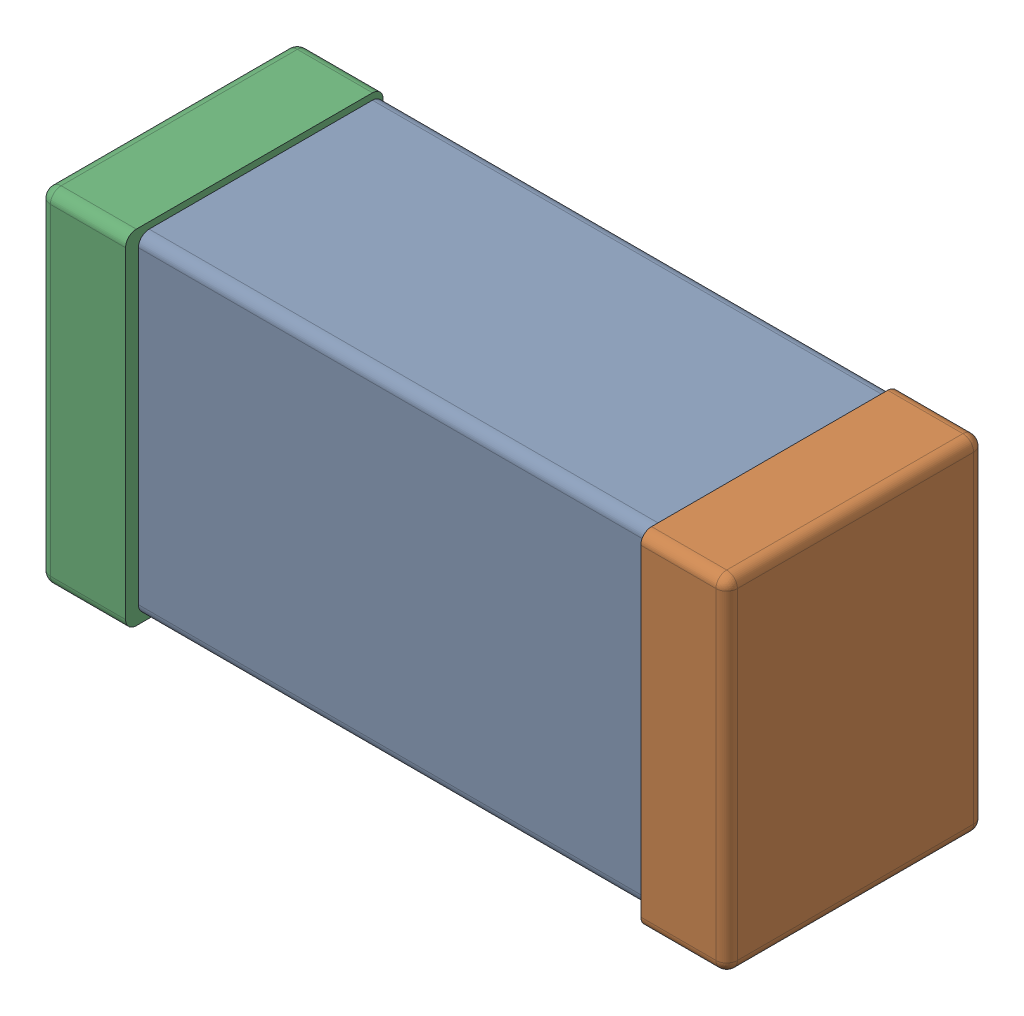
SolidWorks assembly C0603_060_2, configuration Standard. Lengths in mm.
Overall size (1.6 0.8 0.6).
4 component instances, 3 part files, 0 mates.
Components (placement in the parent):
- C0603_060_3-1: C0603_060_3 [Standard] at (0 0 23.8) size (1.6 0.8 0.6)
  - Part 3_1-1: Part 3_1 [Standard] at (0 0 -23.815) size (1.4 0.77 0.57)
  - Part 2_1-1: Part 2_1 [Standard] at (0 0 -23.8) size (0.2 0.8 0.6)
  - Part 1_1-1: Part 1_1 [Standard] at (0 0 -23.8) size (0.2 0.8 0.6)
